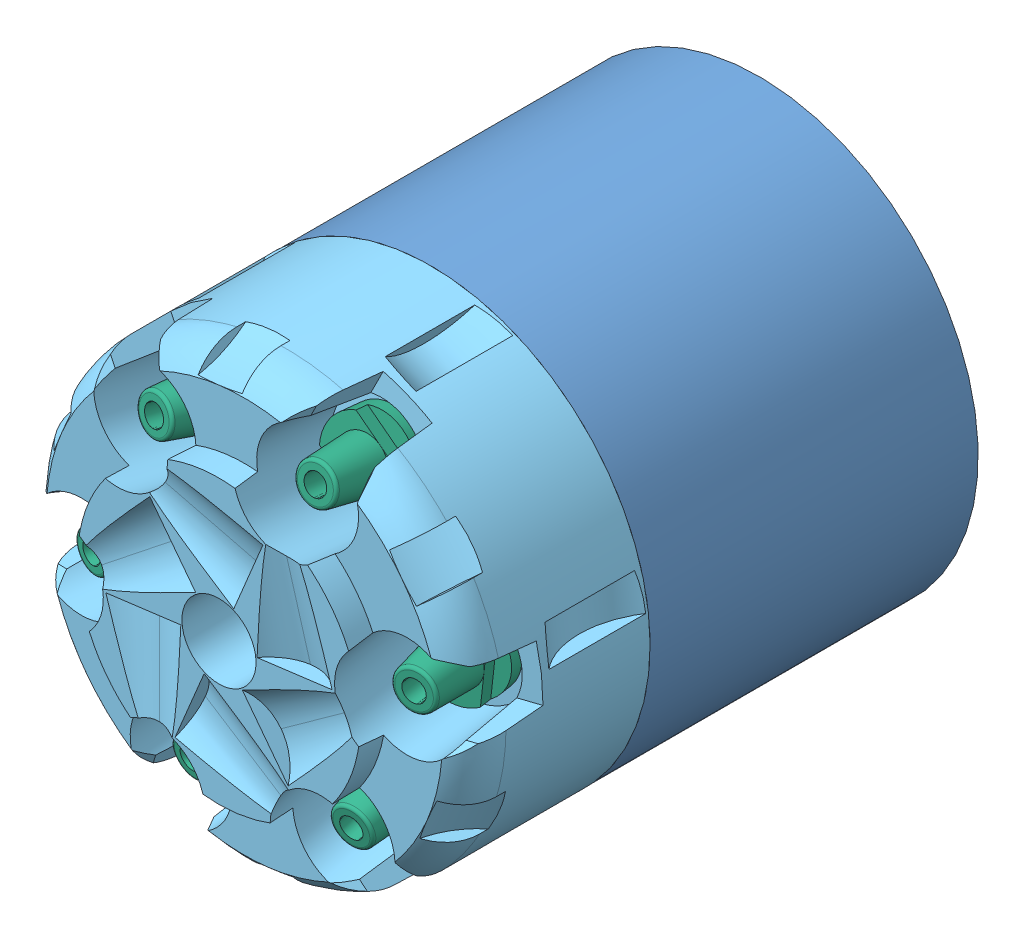
SolidWorks assembly Cylinder_cut_inner_piston.22, configuration Default. Lengths in mm.
Overall size (45.64 44.8 52.12).
21 component instances, 6 part files, 11 mates.
Components (placement in the parent):
- Cylinder_cut.22-2: Cylinder_cut.22 [Default] at (-13.7995 2.1314 7.2207) size (43.32 43.9 52.12)
- Inner_cylinder.22-12: Inner_cylinder.22 [Default] at (5.6893 22.7918 27.8676) size (5.59 5.59 25.4)
- Inner_cylinder.22-13: Inner_cylinder.22 [Default] at (10.5828 34.5112 27.8676) x (0.5 0.866025 0) z (0 0 1) size (5.59 5.59 25.4)
- Inner_cylinder.22-14: Inner_cylinder.22 [Default] at (2.8803 44.6088 27.8676) x (-0.5 0.866025 0) z (0 0 1) size (5.59 5.59 25.4)
- Inner_cylinder.22-15: Inner_cylinder.22 [Default] at (-9.7157 42.9871 27.8676) x (-1 0 0) z (0 0 1) size (5.59 5.59 25.4)
- Inner_cylinder.22-16: Inner_cylinder.22 [Default] at (-14.6092 31.2677 27.8676) x (-0.5 -0.866025 0) z (0 0 1) size (5.59 5.59 25.4)
- Inner_cylinder.22-17: Inner_cylinder.22 [Default] at (-6.9068 21.1701 27.8676) x (0.5 -0.866025 0) z (0 0 1) size (5.59 5.59 25.4)
- Piston.22-9: Piston.22 [Default] at (5.6893 22.7918 53.0026) x (0.293986 0.95581 0) z (0 0 -1) size (4.57 4.57 17)
- Piston.22-10: Piston.22 [Default] at (10.5828 34.5112 53.0026) x (-0.680763 0.732504 0) z (0 0 -1) size (4.57 4.57 17)
- Piston.22-11: Piston.22 [Default] at (2.8803 44.6088 53.0026) x (-0.974748 -0.223306 0) z (0 0 -1) size (4.57 4.57 17)
- Piston.22-12: Piston.22 [Default] at (-9.7157 42.9871 53.0026) x (-0.293986 -0.95581 0) z (0 0 -1) size (4.57 4.57 17)
- Piston.22-13: Piston.22 [Default] at (-14.6092 31.2677 53.0026) x (0.680763 -0.732504 0) z (0 0 -1) size (4.57 4.57 17)
- Piston.22-14: Piston.22 [Default] at (-6.9068 21.1701 53.0026) x (0.974748 0.223306 0) z (0 0 -1) size (4.57 4.57 17)
- Peg-1: Peg [Default] at (-18.4203 39.7404 48.1055) size (2.54 2.54 10.16)
- Back_part_of_cylinder-4: Back_part_of_cylinder [Default] at (-3.8715 42.7701 38.7115) size (43.32 43.9 21.29)
- Nippel-7: Nippel [Default] at (-288.0164 274.3118 121.9102) x (0.459801 -0.496858 -0.736013) z (-0.718341 -0.695384 0.020669) size (12.39 9.96 7.5)
- Nippel-8: Nippel [Default] at (-354.0927 -94.0854 121.9102) x (0.660192 0.149771 -0.736013) z (0.24305 -0.969794 0.020669) size (12.39 9.96 7.5)
- Nippel-9: Nippel [Default] at (-68.0895 -335.5078 121.9102) x (0.200391 0.646629 -0.736013) z (0.961391 -0.27441 0.020669) size (12.39 9.96 7.5)
- Nippel-10: Nippel [Default] at (283.99 -208.5329 121.9102) x (-0.459801 0.496858 -0.736013) z (0.718341 0.695384 0.020669) size (12.39 9.96 7.5)
- Nippel-11: Nippel [Default] at (350.0663 159.8643 121.9102) x (-0.660192 -0.149771 -0.736013) z (-0.24305 0.969794 0.020669) size (12.39 9.96 7.5)
- Nippel-12: Nippel [Default] at (64.0631 401.2867 121.9102) x (-0.200391 -0.646629 -0.736013) z (-0.961391 0.27441 0.020669) size (12.39 9.96 7.5)
Mates (geometry in assembly coordinates):
- Concentric4: concentric: circle of Cylinder_cut.22-2; circle of Inner_cylinder.22-12
- Concentric5: concentric: circle of Cylinder_cut.22-2; cylinder of Piston.22-9 through (5.6893 22.7918 36.0026) axis (0 0 1) radius 1.778
- Lock1: lock: unknown of Cylinder_cut.22-2
- Concentric6: concentric: cylinder of Cylinder_cut.22-2 through (-18.4203 39.7404 48.1055) axis (0 0 1) radius 1.27; cylinder of Peg-1 through (-18.4203 39.7404 58.2655) axis (0 0 -1) radius 1.27
- Distance1: distance = 5.08 mm: plane of Peg-1 through (-18.4203 39.7404 58.2655) normal (0 0 1); plane of Cylinder_cut.22-2 through (-23.7914 57.1314 53.1855) normal (0 0 1)
- Concentric7: concentric: cylinder of Cylinder_cut.22-2 through (-2.0132 32.8895 47.7024) axis (0 0 1) radius 3.5; cylinder of Back_part_of_cylinder-4 through (-2.0132 32.8895 47.7006) axis (0 0 1) radius 3.5
- Concentric8: concentric: cylinder of Cylinder_cut.22-2 through (-2.0132 32.8895 47.7024) axis (0 0 1) radius 20.7; cylinder of Back_part_of_cylinder-4 through (-2.0132 32.8895 47.7006) axis (0 0 1) radius 20.7
- Concentric9: concentric: cylinder of Peg-1 through (-18.4203 39.7404 58.2655) axis (0 0 -1) radius 1.27; cylinder of Back_part_of_cylinder-4 through (-18.4203 39.7404 58.2655) axis (0 0 -1) radius 1.27
- Coincident1: coincident: plane of Cylinder_cut.22-2 through (-23.7914 57.1314 53.1855) normal (0 0 1); plane of Back_part_of_cylinder-4 through (-28.7717 55.1513 53.1855) normal (0 0 -1)
- Concentric10: concentric: cylinder of Back_part_of_cylinder-4 through (-11.4034 45.1995 70.7021) axis (0.105317 -0.138065 -0.984808) radius 2.067; cylinder of Nippel-7 through (-10.6872 44.2606 64.0054) axis (-0.105317 0.138065 0.984808) radius 2.5
- Coincident2: coincident: plane of Back_part_of_cylinder-4 through (-12.2148 42.8552 62.9221) normal (-0.105317 0.138065 0.984808); plane of Nippel-7 through (-9.2239 42.5398 63.2862) normal (0.105317 -0.138065 -0.984808)
